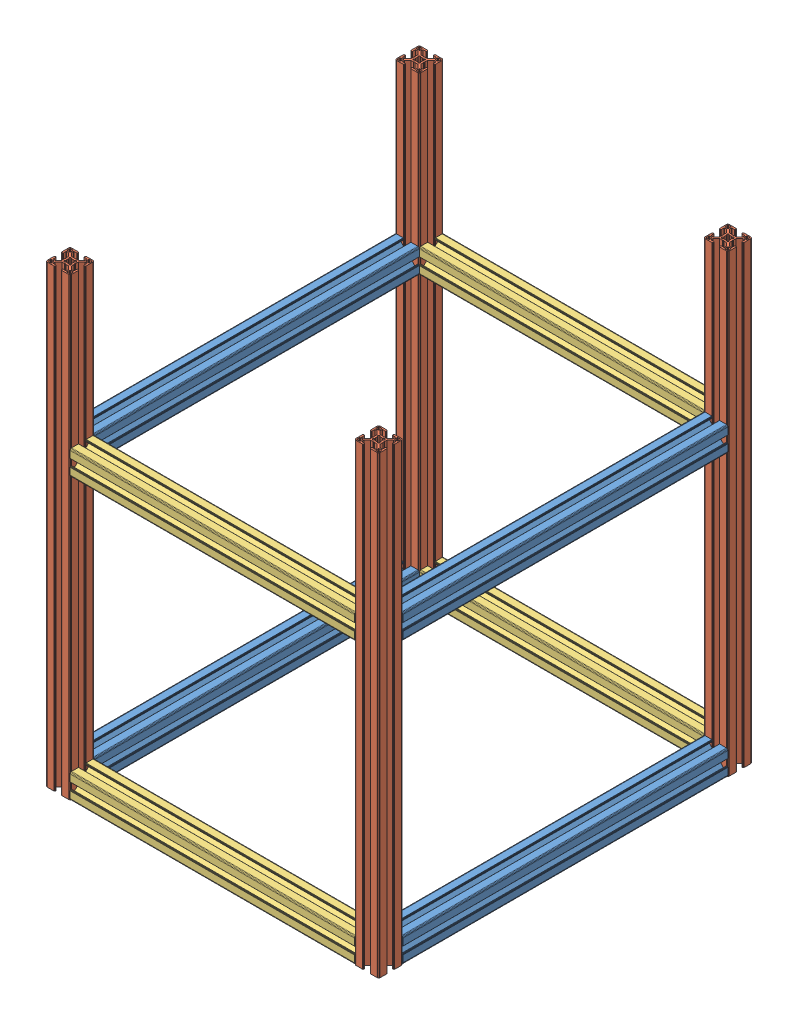
SolidWorks assembly module4_frame_v1.0, configuration Default. Lengths in mm.
Overall size (410 560 460).
12 component instances, 3 part files, 39 mates.
Components (placement in the parent):
- Profile_30x30mm_400mm-3: Profile_30x30mm_400mm [Default] x (1 0 0) z (0 0 -1) size (30 30 400)
- Profile_30x30mm_400mm-4: Profile_30x30mm_400mm [Default] at (-380 0 0) x (1 0 0) z (0 0 -1) size (30 30 400)
- profile_30x30mm_560mm-8: profile_30x30mm_560mm [Default] at (0 -30 -30) x (1 0 0) z (0 -1 0) size (30 30 560)
- profile_30x30mm_560mm-7: profile_30x30mm_560mm [Default] at (0 -30 400) x (1 0 0) z (0 -1 0) size (30 30 560)
- profile_30x30mm_560mm-5: profile_30x30mm_560mm [Default] at (-380 -30 -30) x (1 0 0) z (0 -1 0) size (30 30 560)
- profile_30x30mm_560mm-6: profile_30x30mm_560mm [Default] at (-380 -30 400) x (1 0 0) z (0 -1 0) size (30 30 560)
- Profile_30x30mm_350mm-10: Profile_30x30mm_350mm [Default] at (0 315 0) x (0 0 -1) z (1 0 0) size (30 30 350)
- Profile_30x30mm_350mm-12: Profile_30x30mm_350mm [Default] at (0 315 430) x (0 0 -1) z (1 0 0) size (30 30 350)
- Profile_30x30mm_350mm-9: Profile_30x30mm_350mm [Default] at (0 -30 430) x (0 0 -1) z (1 0 0) size (30 30 350)
- Profile_30x30mm_350mm-11: Profile_30x30mm_350mm [Default] at (0 -30 0) x (0 0 -1) z (1 0 0) size (30 30 350)
- Profile_30x30mm_400mm-6: Profile_30x30mm_400mm [Default] at (0 315 400) size (30 30 400)
- Profile_30x30mm_400mm-7: Profile_30x30mm_400mm [Default] at (-380 315 400) size (30 30 400)
Mates (geometry in assembly coordinates):
- Coincident1: coincident: plane of assembly; plane of assembly; plane of Profile_30x30mm_400mm-3 through (0 0 400) normal (0 0 1); plane of Profile_30x30mm_400mm-4 through (-380 0 400) normal (0 0 1)
- Coincident7: coincident: plane of assembly; plane of assembly; plane of Profile_30x30mm_400mm-3 through (10.25 -30 400) normal (0 -1 0); plane of Profile_30x30mm_400mm-4 through (-352 -30 400) normal (0 -1 0)
- Coincident24: coincident: plane of assembly; plane of assembly; plane of profile_30x30mm_560mm-8 through (0 -30 -30) normal (0 -1 0); plane of profile_30x30mm_560mm-7 through (0 -30 400) normal (0 -1 0)
- Coincident26: coincident: plane of assembly; plane of assembly; plane of profile_30x30mm_560mm-5 through (-380 -30 -30) normal (0 -1 0); plane of profile_30x30mm_560mm-6 through (-380 -30 400) normal (0 -1 0)
- Coincident27: coincident: plane of profile_30x30mm_560mm-5 through (-350 530 -10.25) normal (1 0 0); plane of profile_30x30mm_560mm-6 through (-350 530 419.75) normal (1 0 0)
- Coincident28: coincident: plane of profile_30x30mm_560mm-7 through (19.75 530 400) normal (0 0 -1); plane of profile_30x30mm_560mm-6 through (-378 530 400) normal (0 0 -1)
- Coincident30: coincident: plane of profile_30x30mm_560mm-8 through (10.25 530 0) normal (0 0 1); plane of profile_30x30mm_560mm-5 through (-369.75 530 0) normal (0 0 1)
- Coincident29: coincident: plane of assembly; plane of assembly; plane of profile_30x30mm_560mm-8 through (0 530 -19.75) normal (-1 0 0); plane of profile_30x30mm_560mm-7 through (0 530 428) normal (-1 0 0)
- Coincident32: coincident: plane of assembly; plane of assembly; plane of Profile_30x30mm_400mm-3 through (30 -2 400) normal (1 0 0); plane of profile_30x30mm_560mm-8 through (30 530 -28) normal (1 0 0)
- Coincident35: coincident: plane of Profile_30x30mm_400mm-4 through (-380 -10.25 400) normal (-1 0 0); plane of profile_30x30mm_560mm-6 through (-380 530 428) normal (-1 0 0)
- Coincident40: coincident: plane of assembly through (0 0 0) normal (0 0 1); plane of Profile_30x30mm_400mm-3 through (0 0 0) normal (0 0 -1); plane of assembly
- Coincident41: coincident: plane of assembly through (0 0 0) normal (0 1 0); plane of Profile_30x30mm_400mm-3 through (0 0 0) normal (0 -1 0); plane of assembly
- Coincident42: coincident: plane of assembly through (0 0 0) normal (1 0 0); plane of Profile_30x30mm_400mm-3 through (0 0 0) normal (1 0 0); plane of assembly
- Distance27: distance = 30 mm: plane of assembly; plane of assembly; plane of Profile_30x30mm_400mm-3 through (19.75 0 400) normal (0 1 0); plane of profile_30x30mm_560mm-8 through (0 -30 -30) normal (0 -1 0); plane of assembly; plane of assembly; plane of Profile_30x30mm_400mm-3; plane of profile_30x30mm_560mm-7
- Distance28: distance = 30 mm: plane of Profile_30x30mm_400mm-3 through (0 0 400) normal (0 0 1); plane of profile_30x30mm_560mm-7 through (10.25 530 430) normal (0 0 1)
- Coincident85: coincident: plane of assembly; plane of assembly; plane of profile_30x30mm_560mm-8 through (0 530 -19.75) normal (-1 0 0); plane of Profile_30x30mm_350mm-10 through (0 315 0) normal (1 0 0)
- Coincident86: coincident: plane of profile_30x30mm_560mm-8 through (2 530 -30) normal (0 0 -1); plane of Profile_30x30mm_350mm-10 through (-350 334.75 -30) normal (0 0 -1)
- Coincident88: coincident: plane of profile_30x30mm_560mm-5 through (-350 530 -28) normal (1 0 0); plane of Profile_30x30mm_350mm-10 through (-350 315 0) normal (-1 0 0)
- Coincident101: coincident: plane of assembly through (0 0 0) normal (0 0 1); plane of Profile_30x30mm_400mm-3 through (0 0 0) normal (0 0 -1); plane of assembly
- Coincident102: coincident: plane of assembly through (0 0 0) normal (0 1 0); plane of Profile_30x30mm_400mm-3 through (0 0 0) normal (0 -1 0); plane of assembly
- Coincident103: coincident: plane of assembly through (0 0 0) normal (1 0 0); plane of Profile_30x30mm_400mm-3 through (0 0 0) normal (1 0 0); plane of assembly
- Coincident112: coincident: plane of assembly; plane of assembly; plane of Profile_30x30mm_350mm-12 through (-350 315 430) normal (-1 0 0); plane of Profile_30x30mm_350mm-9 through (-350 -30 430) normal (-1 0 0)
- Coincident113: coincident: plane of Profile_30x30mm_350mm-9 through (-350 -30 430) normal (-1 0 0); plane of Profile_30x30mm_350mm-11 through (-350 -30 0) normal (-1 0 0)
- Coincident114: coincident: plane of Profile_30x30mm_350mm-9 through (-350 -30 410.25) normal (0 -1 0); plane of Profile_30x30mm_350mm-11 through (-350 -30 -19.75) normal (0 -1 0)
- Coincident116: coincident: plane of profile_30x30mm_560mm-7 through (0 530 428) normal (-1 0 0); plane of Profile_30x30mm_350mm-11 through (0 -30 0) normal (1 0 0)
- Coincident117: coincident: plane of profile_30x30mm_560mm-7 through (0 -30 400) normal (0 -1 0); plane of Profile_30x30mm_350mm-9 through (-350 -30 428) normal (0 -1 0)
- Coincident118: coincident: plane of profile_30x30mm_560mm-7 through (28 530 430) normal (0 0 1); plane of Profile_30x30mm_350mm-9 through (-350 -19.75 430) normal (0 0 1)
- Coincident119: coincident: plane of profile_30x30mm_560mm-8 through (19.75 530 -30) normal (0 0 -1); plane of Profile_30x30mm_350mm-11 through (-350 -28 -30) normal (0 0 -1)
- Coincident120: coincident: plane of profile_30x30mm_560mm-7 through (28 530 430) normal (0 0 1); plane of Profile_30x30mm_350mm-12 through (-350 343 430) normal (0 0 1)
- Distance43: distance = 185 mm: plane of profile_30x30mm_560mm-5 through (-380 530 -30) normal (0 1 0); plane of Profile_30x30mm_350mm-10 through (-350 345 -10.25) normal (0 1 0)
- Coincident134: coincident: plane of Profile_30x30mm_350mm-10 through (-350 345 -10.25) normal (0 1 0); plane of Profile_30x30mm_350mm-12 through (-350 345 419.75) normal (0 1 0)
- Coincident236: coincident: plane of profile_30x30mm_560mm-7 through (0 -30 400) normal (0 -1 0); plane of profile_30x30mm_560mm-5 through (-380 -30 -30) normal (0 -1 0)
- Coincident247: coincident: plane of Profile_30x30mm_350mm-12 through (-350 345 402) normal (0 1 0); plane of Profile_30x30mm_400mm-6 through (28 345 0) normal (0 1 0)
- Coincident248: coincident: plane of profile_30x30mm_560mm-7 through (2 530 400) normal (0 0 -1); plane of Profile_30x30mm_400mm-6 through (0 315 400) normal (0 0 1)
- Coincident249: coincident: plane of profile_30x30mm_560mm-7 through (30 530 419.75) normal (1 0 0); plane of Profile_30x30mm_400mm-6 through (30 334.75 0) normal (1 0 0)
- Coincident271: coincident: plane of profile_30x30mm_560mm-5 through (-352 530 0) normal (0 0 1); plane of Profile_30x30mm_400mm-7 through (-380 315 0) normal (0 0 -1)
- Coincident272: coincident: plane of Profile_30x30mm_400mm-6 through (19.75 315 0) normal (0 -1 0); plane of Profile_30x30mm_400mm-7 through (-360.25 315 0) normal (0 -1 0)
- Coincident273: coincident: plane of profile_30x30mm_560mm-5 through (-380 530 -2) normal (-1 0 0); plane of Profile_30x30mm_400mm-7 through (-380 343 0) normal (-1 0 0)
- Coincident274: coincident: plane of profile_30x30mm_560mm-6 through (-378 530 400) normal (0 0 -1); plane of Profile_30x30mm_400mm-7 through (-380 315 400) normal (0 0 1)
